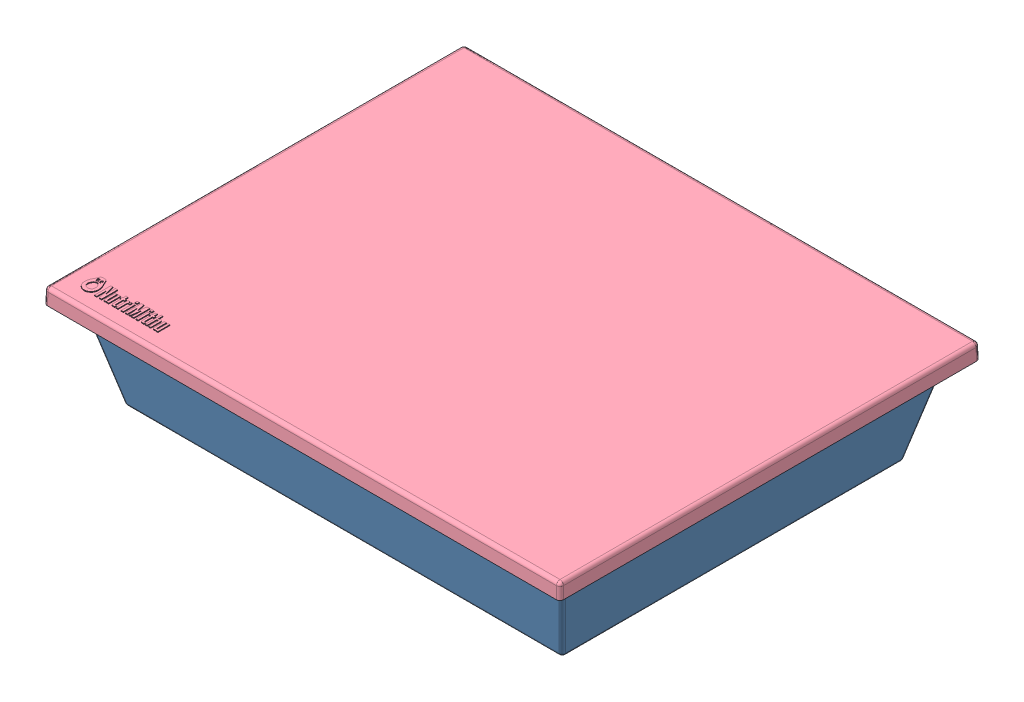
SolidWorks assembly assembly1, configuration Default. Lengths in mm.
Overall size (215.17 43.3 175.17).
4 component instances, 4 part files, 9 mates.
Components (placement in the parent):
- box-1: box [Default] at (77.2618 57.7516 183.9278) size (210 41.5 170)
- divider_long-1: divider_long [Default] at (-20.7382 97.7516 181.9278) size (198 40 10)
- divider_short-1: divider_short [Default] at (77.7618 97.7516 261.9278) x (0 0 -1) z (1 0 0) size (158 40 10)
- lid_with_logo-1: lid_with_logo [Default] at (21.4759 -18.2987 -1.2575) size (215.17 6.8 175.17)
Mates (geometry in assembly coordinates):
- Coincident1: coincident anti-aligned: plane of box-1 through (-12.7382 57.7516 113.9278) normal (0 1 0); plane of divider_long-1 through (-10.7382 57.7516 183.4278) normal (0 -1 0)
- Coincident2: coincident anti-aligned: plane of box-1 through (-12.7382 57.7516 113.9278) normal (0 1 0); plane of divider_short-1 through (79.2618 57.7516 251.9278) normal (0 -1 0)
- Coincident3: coincident anti-aligned: plane of divider_long-1 through (-20.7382 97.7516 181.9278) normal (0 0 -1); plane of divider_short-1 through (79.2618 57.7516 181.9278) normal (0 0 1)
- Coincident4: coincident anti-aligned: plane of divider_long-1 through (79.2618 97.7516 183.4278) normal (-1 0 0); plane of divider_short-1 through (79.2618 97.7516 261.9278) normal (1 0 0)
- Coincident7: coincident anti-aligned: plane of box-1 through (167.2618 57.7516 113.9278) normal (-0.970143 0.242536 0); plane of divider_long-1 through (167.2618 57.7516 183.4278) normal (0.970143 -0.242536 0)
- Coincident8: coincident anti-aligned: plane of box-1 through (-12.7382 57.7516 113.9278) normal (0 0.242536 0.970143); plane of divider_short-1 through (79.2618 57.7516 113.9278) normal (0 -0.242536 -0.970143)
- Coincident9: coincident: plane of box-1 through (77.2618 97.7516 183.9278) normal (0 1 0); plane of lid_with_logo-1 through (-31.4531 97.7516 270.4019) normal (0 -1 0)
- Coincident12: coincident: line of box-1 through (-27.7382 97.7516 268.9278) axis (1 0 0); line of lid_with_logo-1 through (181.3137 97.7516 268.9278) axis (-1 0 0)
- Coincident13: coincident anti-aligned: line of box-1 through (-27.7382 97.7516 98.9278) axis (0 0 1); line of lid_with_logo-1 through (-27.7382 97.7516 268.9278) axis (0 0 -1)
